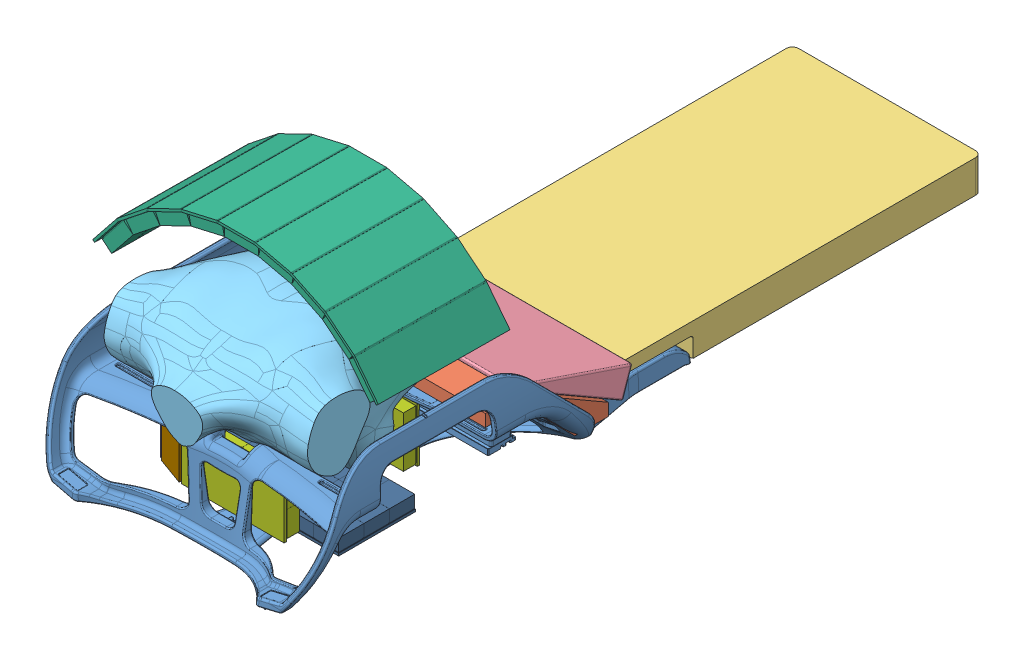
SolidWorks assembly PETMR_SentinelleDetector_V2, configuration Default. Lengths in mm.
Overall size (611.09 652.69 1488.18).
60 component instances, 11 part files, 13 mates.
Components (placement in the parent):
- Patient Support Assembly-1: Patient Support Assembly [Default] at (-6.6077 8.4543 170.0496) size (567.96 275.89 880.18)
- detectorassem-1: detectorassem [Default] at (-15.3966 -42.5515 66.6837) x (1 0 0) z (0 -1 0) size (517.67 317.54 193) (hidden)
  - 52mmTOPBOTTOM-1: 52mmTOPBOTTOM [Default] at (-69.8528 -35.4842 8.7442) size (210.55 32 113)
  - SideDetector-1: SideDetector [Default] at (215.9367 233.9438 -54.2197) x (-0.242515 0.970148 0) z (0 0 1) size (268 155.36 165) (hidden)
    - 52mmX4-1: 52mmX4 [Default] at (-99.1405 6.5957 36.9639) size (60 32 165)
    - 52mmX4-2: 52mmX4 [Default] at (-35.1412 22.594 36.9639) x (0.882373 0.47055 0) z (0 0 1) size (60 32 165)
    - 52mmX4-3: 52mmX4 [Default] at (-163.1399 22.594 36.9639) x (0.882373 -0.47055 0) z (0 0 1) size (60 32 165)
    - 52mmX4-4: 52mmX4 [Default] at (-212.0831 66.8254 36.9639) x (0.557166 -0.830401 0) z (0 0 1) size (60 32 165)
    - 52mmX3-1: 52mmX3 [Default] at (-234.4563 128.8843 62.9639) x (0.100883 -0.994898 0) z (0 0 1) size (60 32 113)
    - 52mmX3-2: 52mmX3 [Default] at (13.802 66.8254 62.9639) x (0.557166 0.830401 0) z (0 0 1) size (60 32 113)
  - SideDetector-2: SideDetector [Default] at (-199.3424 -27.5859 -54.2197) x (0.242515 -0.970148 0) z (0 0 1) size (268 155.36 165)
    - 52mmX4-1: 52mmX4 [Default] at (-99.1405 6.5957 36.9639) size (60 32 165)
    - 52mmX4-2: 52mmX4 [Default] at (-35.1412 22.594 36.9639) x (0.882373 0.47055 0) z (0 0 1) size (60 32 165)
    - 52mmX4-3: 52mmX4 [Default] at (-163.1399 22.594 36.9639) x (0.882373 -0.47055 0) z (0 0 1) size (60 32 165)
    - 52mmX4-4: 52mmX4 [Default] at (-212.0831 66.8254 36.9639) x (0.557166 -0.830401 0) z (0 0 1) size (60 32 165)
    - 52mmX3-1: 52mmX3 [Default] at (-234.4563 128.8843 62.9639) x (0.100883 -0.994898 0) z (0 0 1) size (60 32 113)
    - 52mmX3-2: 52mmX3 [Default] at (13.802 66.8254 62.9639) x (0.557166 0.830401 0) z (0 0 1) size (60 32 113)
  - 52mmTOPBOTTOM-2: 52mmTOPBOTTOM [Default] at (86.4472 241.8421 8.7442) x (-1 0 0) z (0 0 1) size (210.55 32 113)
  - 52mmAnterior-2: 52mmAnterior [Default] at (34.3328 154.0821 93.2442) x (1 0 0) z (0 1 0) size (312.06 32 157.26)
- woman body_V2-1: woman body_V2 [Default] at (14.8986 194.9364 -387.735) x (1 0 0) z (0 -0.087156 0.996195) size (447.45 303.26 512.25) (hidden)
- PAD_RAMP-1: PAD_RAMP [Default] at (-5.6021 38.7846 43.1459) size (500 131.73 252.08)
- PAD_BODY-1: PAD_BODY [Default] at (-7.458 -146.0499 -620.6853) size (388.02 103.9 823.5)
- PAD_HIP_WEDGE-1: PAD_HIP_WEDGE [Default] at (-7.7622 30.991 -148.2616) x (1 0 0) z (0 -0.320449 -0.947266) size (482.6 58.99 260.35)
- Assem1-1: Assem1 [Default] at (-182.8625 -485.9928 -891.4551) size (737.79 527.61 549.47)
  - woman body-1: woman body [Default] at (196.8565 709.5111 506.493) x (1 0 0) z (0 -0.139173 0.990268) size (426.88 303.26 512.25)
  - CshapedDetector1-2: CshapedDetector1 [Default] at (462.29 915.1834 874.4586) x (-0.900926 0.433957 -0.003787) z (0 0.008727 0.999962) size (527.59 312.86 270)
    - 5Detector-1: 5Detector [Default] at (91.8512 126.8436 184.2598) size (80 32 270)
    - 5Detector-2: 5Detector [Default] at (168.0955 135.4362 184.2598) x (0.974917 0.22257 0) z (0 0 1) size (80 32 270)
    - 5Detector-4: 5Detector [Default] at (240.515 160.783 184.2598) x (0.900926 0.433974 0) z (0 0 1) size (80 32 270)
    - 5Detector-5: 5Detector [Default] at (305.4764 201.6123 184.2598) x (0.781738 0.623607 0) z (0 0 1) size (80 32 270)
    - 5Detector-6: 5Detector [Default] at (359.7211 255.8759 184.2598) x (0.623334 0.781956 0) z (0 0 1) size (80 32 270)
    - 5Detector-7: 5Detector [Default] at (400.5278 320.8517 184.2598) x (0.433659 0.901077 0) z (0 0 1) size (80 32 270)
    - 5Detector-8: 5Detector [Default] at (15.6069 135.4362 184.2598) x (0.974917 -0.22257 0) z (0 0 1) size (80 32 270)
    - 5Detector-9: 5Detector [Default] at (-56.8125 160.783 184.2598) x (0.900926 -0.433974 0) z (0 0 1) size (80 32 270)
    - 5Detector-10: 5Detector [Default] at (425.8492 393.2799 184.2598) x (0.222229 0.974994 0) z (0 0 1) size (80 32 270)
  - detectorassem-1: detectorassem [Default] at (165.9838 443.4414 957.2963) x (1 0 0) z (0 -1 0) size (517.67 317.54 193)
    - 52mmTOPBOTTOM-1: 52mmTOPBOTTOM [Default] at (-69.8528 -35.4842 8.7442) size (210.55 32 113)
    - SideDetector-1: SideDetector [Default] at (215.9367 233.9438 -54.2197) x (-0.242515 0.970148 0) z (0 0 1) size (268 155.36 165) (hidden)
      - 52mmX4-1: 52mmX4 [Default] at (-99.1405 6.5957 36.9639) size (60 32 165)
      - 52mmX4-2: 52mmX4 [Default] at (-35.1412 22.594 36.9639) x (0.882373 0.47055 0) z (0 0 1) size (60 32 165)
      - 52mmX4-3: 52mmX4 [Default] at (-163.1399 22.594 36.9639) x (0.882373 -0.47055 0) z (0 0 1) size (60 32 165)
      - 52mmX4-4: 52mmX4 [Default] at (-212.0831 66.8254 36.9639) x (0.557166 -0.830401 0) z (0 0 1) size (60 32 165)
      - 52mmX3-1: 52mmX3 [Default] at (-234.4563 128.8843 62.9639) x (0.100883 -0.994898 0) z (0 0 1) size (60 32 113)
      - 52mmX3-2: 52mmX3 [Default] at (13.802 66.8254 62.9639) x (0.557166 0.830401 0) z (0 0 1) size (60 32 113)
    - SideDetector-2: SideDetector [Default] at (-199.3424 -27.5859 -54.2197) x (0.242515 -0.970148 0) z (0 0 1) size (268 155.36 165)
      - 52mmX4-1: 52mmX4 [Default] at (-99.1405 6.5957 36.9639) size (60 32 165)
      - 52mmX4-2: 52mmX4 [Default] at (-35.1412 22.594 36.9639) x (0.882373 0.47055 0) z (0 0 1) size (60 32 165)
      - 52mmX4-3: 52mmX4 [Default] at (-163.1399 22.594 36.9639) x (0.882373 -0.47055 0) z (0 0 1) size (60 32 165)
      - 52mmX4-4: 52mmX4 [Default] at (-212.0831 66.8254 36.9639) x (0.557166 -0.830401 0) z (0 0 1) size (60 32 165)
      - 52mmX3-1: 52mmX3 [Default] at (-234.4563 128.8843 62.9639) x (0.100883 -0.994898 0) z (0 0 1) size (60 32 113)
      - 52mmX3-2: 52mmX3 [Default] at (13.802 66.8254 62.9639) x (0.557166 0.830401 0) z (0 0 1) size (60 32 113)
    - 52mmTOPBOTTOM-2: 52mmTOPBOTTOM [Default] at (86.4472 241.8421 8.7442) x (-1 0 0) z (0 0 1) size (210.55 32 113)
    - 52mmAnterior-2: 52mmAnterior [Default] at (34.3328 154.0821 93.2442) x (1 0 0) z (0 1 0) size (312.06 32 157.26)
  - SideDetector-1: SideDetector [Default] at (593.6345 497.6611 1191.1169) x (-0.258819 0 0.965926) z (0 -1 0) size (268 155.36 165) (hidden)
    - 52mmX4-1: 52mmX4 [Default] at (-99.1405 6.5957 36.9639) size (60 32 165)
    - 52mmX4-2: 52mmX4 [Default] at (-35.1412 22.594 36.9639) x (0.882373 0.47055 0) z (0 0 1) size (60 32 165)
    - 52mmX4-3: 52mmX4 [Default] at (-163.1399 22.594 36.9639) x (0.882373 -0.47055 0) z (0 0 1) size (60 32 165)
    - 52mmX4-4: 52mmX4 [Default] at (-212.0831 66.8254 36.9639) x (0.557166 -0.830401 0) z (0 0 1) size (60 32 165)
    - 52mmX3-1: 52mmX3 [Default] at (-234.4563 128.8843 62.9639) x (0.100883 -0.994898 0) z (0 0 1) size (60 32 113)
    - 52mmX3-2: 52mmX3 [Default] at (13.802 66.8254 62.9639) x (0.557166 0.830401 0) z (0 0 1) size (60 32 113)
Mates (geometry in assembly coordinates):
- Tangent1: tangent aligned: cylinder of Patient Support Assembly-1 through (-6.6077 156.2043 55.0188) axis (0 0 1) radius 292; plane of detectorassem-1/52mmAnterior-2 through (18.9362 -135.7957 220.7658) normal (0 -1 0)
- Coincident1: coincident anti-aligned: plane of Patient Support Assembly-1 through (236.3923 -20.4457 31.1996) normal (0 0 1); plane of detectorassem-1/52mmTOPBOTTOM-1 through (-85.2494 -51.2957 31.1996) normal (0 0 -1)
- Parallel1: parallel aligned: plane of Patient Support Assembly-1 through (-84.9 -139.9608 -432.1862) normal (0 0.087156 -0.996195); plane of woman body_V2-1 through (-357.0688 -53.7173 -71.4741) normal (0 0.087156 -0.996195)
- Coincident2: coincident anti-aligned: plane of Patient Support Assembly-1 through (-237.4401 -67.5457 -375.1868) normal (0 1 0); plane of PAD_RAMP-1 through (244.3979 -67.5457 -208.9353) normal (0 -1 0)
- Distance1: distance = 7.5849 mm: line of PAD_RAMP-1 through (-255.6021 38.7846 43.1459) axis (1 0 0); line of Patient Support Assembly-1 through (169.6194 31.4543 45.0947) axis (1 0 0)
- Distance3: distance = 21.4395 mm: plane of PAD_RAMP-1 through (244.3979 38.7846 43.1459) normal (1 0 0); line of Patient Support Assembly-1 through (265.8374 49.2713 -7.7979) axis (0 0 1)
- Coincident8: coincident anti-aligned: plane of PAD_RAMP-1 through (244.3979 -42.1457 -208.9353) normal (0 0 -1); plane of PAD_BODY-1 through (-7.458 -146.0499 -208.9353) normal (0 0 1)
- Coincident12: coincident aligned: line of PAD_RAMP-1 through (244.3979 -42.1457 -208.9353) axis (-1 0 0); line of PAD_BODY-1 through (173.8524 -42.1457 -208.9353) axis (-1 0 0)
- Coincident16: coincident anti-aligned: plane of PAD_RAMP-1 through (244.3979 64.1858 -24.7637) normal (0 0.866025 -0.5); plane of PAD_HIP_WEDGE-1 through (-249.0622 65.4873 -22.5095) normal (0 -0.866025 0.5)
- Coincident17: coincident: line of PAD_RAMP-1 through (244.3979 64.1858 -24.7637) axis (-1 0 0); cylinder of PAD_HIP_WEDGE-1 through (-249.0622 66.9355 -26.3512) axis (1 0 0) radius 3.175
- Parallel8: parallel anti-aligned: line of Patient Support Assembly-1 through (-37.8107 -134.1237 59.9149) axis (0 0 1); line of Assem1-1/detectorassem-1/52mmAnterior-2 through (-164.58 -135.7957 246.9747) axis (0 0 -1)
- Parallel9: parallel aligned: line of Patient Support Assembly-1 through (24.5953 -134.1237 214.0157) axis (0 0 -1); line of Assem1-1/detectorassem-1/52mmAnterior-2 through (147.4794 -135.7957 246.9747) axis (0 0 -1)
- Tangent6: tangent aligned: cylinder of Patient Support Assembly-1 through (-6.6077 156.2043 55.0188) axis (0 0 1) radius 292; plane of Assem1-1/detectorassem-1/52mmAnterior-2 through (17.4541 -135.7957 219.9232) normal (0 -1 0)
